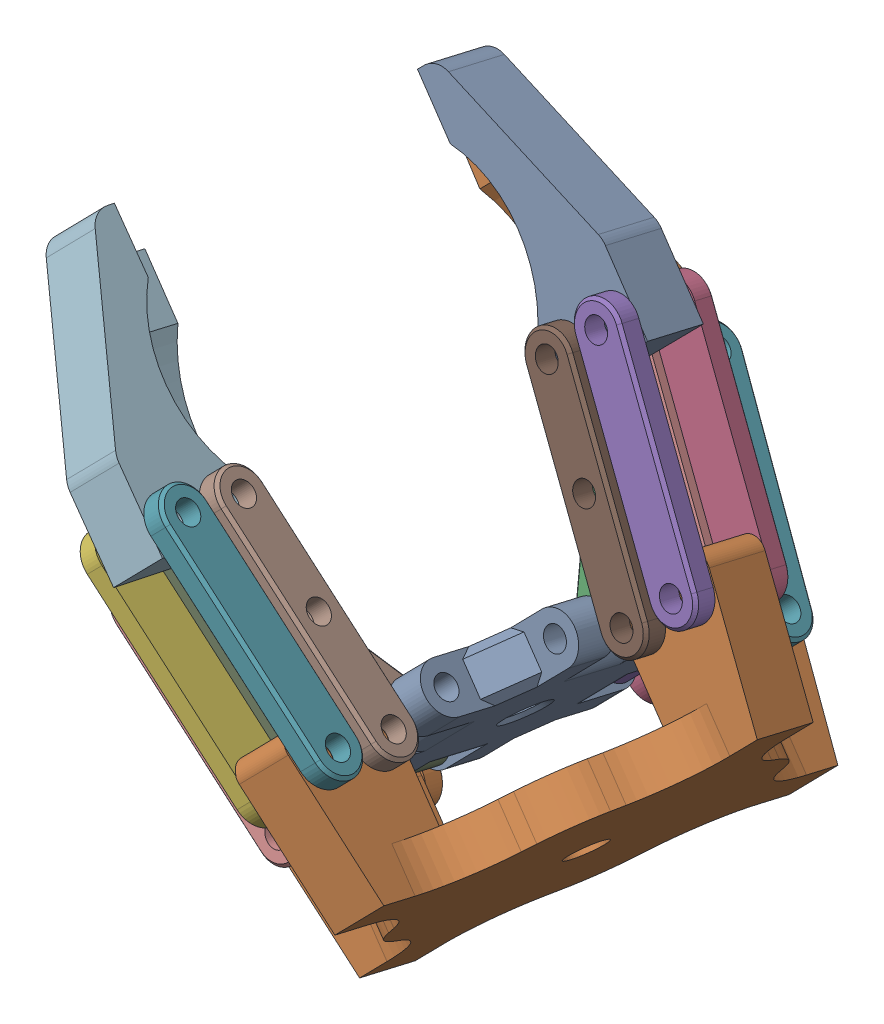
SolidWorks assembly total, configuration Default. Lengths in mm.
Overall size (103.68 109.85 90.72).
26 component instances, 6 part files, 67 mates.
Components (placement in the parent):
- Elevetor_part-1: Elevetor_part [Default] at (64.4019 9.7724 30.449) x (0.689493 0.705559 -0.163663) z (0 0.225963 0.974136) size (39.95 6.2 39.95)
- Gripper1_part-7: Gripper1_part [Default] at (45.2763 21.6653 1.1461) x (-0.017226 0.241873 0.970155) z (0.724087 -0.666096 0.178924) size (13.75 7.7 33.83)
- Connecting_rod_2_part-12: Connecting_rod_2_part [Default] at (53.0008 5.7158 -3.298) x (-0.708443 0.60995 -0.355063) z (-0.150692 0.36076 0.920404) size (33 2.7 6.5)
- Connecting_rod_3_part-10: Connecting_rod_3_part [Default] at (52.9016 7.626 4.2136) x (-0.70843 0.609919 -0.355141) z (-0.150752 0.360811 0.920374) size (33 2.7 6.5)
- Connecting_rod_1_part-5: Connecting_rod_1_part [Default] at (59.8022 9.0845 7.7997) x (0.555901 -0.370654 0.744036) z (-0.464299 0.603988 0.647784) size (19.5 7.7 5.2)
- Connecting_rod_3_part-11: Connecting_rod_3_part [Default] at (60.0724 14.9638 2.5115) x (0.70843 -0.609919 0.355141) z (-0.150752 0.360811 0.920374) size (33 2.7 6.5)
- Connecting_rod_2_part-13: Connecting_rod_2_part [Default] at (60.1715 13.0536 -5.0001) x (0.708443 -0.60995 0.355063) z (-0.150692 0.36076 0.920404) size (33 2.7 6.5)
- Connecting_rod_1_part-6: Connecting_rod_1_part [Default] at (61.1212 17.5589 49.8903) x (-0.555901 0.660356 0.504881) z (-0.464299 0.257131 -0.847531) size (19.5 7.7 5.2)
- Connecting_rod_1_part-7: Connecting_rod_1_part [Default] at (44.4481 -1.6146 33.039) x (0.997863 -0.063651 0.014765) z (0.065341 0.972054 -0.22548) size (19.5 7.7 5.2)
- Connecting_rod_2_part-14: Connecting_rod_2_part [Default] at (33.1537 -5.5281 39.2849) x (-0.851154 0.51134 -0.118612) z (0.524916 0.829139 -0.192329) size (33 2.7 6.5)
- Connecting_rod_3_part-12: Connecting_rod_3_part [Default] at (38.4973 -0.06 38.0165) x (-0.851154 0.51134 -0.118612) z (0.524916 0.829139 -0.192329) size (33 2.7 6.5)
- Gripper1_part-8: Gripper1_part [Default] at (27.5496 9.2689 30.5144) x (0.689493 0.705559 -0.163663) z (0.724292 -0.67166 0.1558) size (13.75 7.7 33.83)
- Connecting_rod_2_part-15: Connecting_rod_2_part [Default] at (33.1537 -7.8781 29.1538) x (-0.851154 0.51134 -0.118612) z (-0.524916 -0.829139 0.192329) size (33 2.7 6.5)
- Connecting_rod_3_part-13: Connecting_rod_3_part [Default] at (38.4973 -2.41 27.8855) x (-0.851154 0.51134 -0.118612) z (-0.524916 -0.829139 0.192329) size (33 2.7 6.5)
- Connecting_rod_1_part-8: Connecting_rod_1_part [Default] at (75.3578 27.439 26.2997) x (-0.113909 0.967795 -0.224492) z (-0.993491 -0.110963 0.025739) size (19.5 7.7 5.2)
- Connecting_rod_2_part-16: Connecting_rod_2_part [Default] at (79.774 39.7793 18.0991) x (-0.564923 0.803802 -0.186452) z (-0.825143 -0.550312 0.127652) size (33 2.7 6.5)
- Connecting_rod_2_part-17: Connecting_rod_2_part [Default] at (79.774 42.1293 28.2301) x (-0.564923 0.803802 -0.186452) z (0.825143 0.550312 -0.127652) size (33 2.7 6.5)
- Connecting_rod_2_part-18: Connecting_rod_2_part [Default] at (52.987 21.0669 62.5177) x (0.708435 -0.703979 -0.050332) z (-0.150727 -0.081241 -0.985231) size (33 2.7 6.5)
- Connecting_rod_2_part-19: Connecting_rod_2_part [Default] at (60.1578 28.4047 60.8156) x (0.708435 -0.703979 -0.050332) z (0.150727 0.081241 0.985231) size (33 2.7 6.5)
- Connecting_rod_3_part-14: Connecting_rod_3_part [Default] at (60.0724 26.7328 53.2481) x (0.70843 -0.703982 -0.050366) z (0.150752 0.081217 0.98523) size (33 2.7 6.5)
- Connecting_rod_3_part-15: Connecting_rod_3_part [Default] at (52.9016 19.395 54.9502) x (-0.70843 0.703982 0.050366) z (0.150752 0.081217 0.98523) size (33 2.7 6.5)
- Connecting_rod_3_part-16: Connecting_rod_3_part [Default] at (74.4082 34.3319 19.3627) x (0.564921 -0.803803 0.186452) z (0.825145 0.55031 -0.127651) size (33 2.7 6.5)
- Connecting_rod_3_part-17: Connecting_rod_3_part [Default] at (74.4082 36.6819 29.4937) x (-0.564921 0.803803 -0.186452) z (0.825145 0.55031 -0.127651) size (33 2.7 6.5)
- Gripper1_part-9: Gripper1_part [Default] at (45.3292 33.3645 51.499) x (-0.011012 -0.215725 -0.976392) z (0.724209 -0.675018 0.140971) size (13.75 7.7 33.83)
- Gripper1_part-10: Gripper1_part [Default] at (63.1142 45.6673 22.0714) x (-0.69236 -0.70289 0.163044) z (0.721553 -0.674452 0.156448) size (13.75 7.7 33.83)
- Base_part-1: Base_part [Default] at (77.0657 -1.9712 33.1731) x (0.689493 0.705559 -0.163663) z (0 0.225963 0.974136) size (69.65 19.1 69.65)
Mates (geometry in assembly coordinates):
- Coincidente1: coincident anti-aligned: plane of Part1-1 through (64.8456 17.6341 42.3811) normal (-0.689493 -0.705559 0.163663); plane of Part2-1 through (67.0909 16.3372 46.2492) normal (0.689493 0.705559 -0.163663)
- Concentrico2: concentric aligned: cylinder of Part1-1 through (78.4331 27.9437 43.557) axis (-0.689493 -0.705559 0.163663) radius 1.5; cylinder of Part2-1 through (67.0909 16.3372 46.2492) axis (-0.689493 -0.705559 0.163663) radius 1.5
- Coincidente3: coincident anti-aligned: plane of Part1-1 through (48.1254 -3.3848 29.4974) normal (0 0.225963 0.974136); plane of Part2-3 through (38.4973 -2.105 29.2005) normal (0 -0.225963 -0.974136)
- Concentrico4: concentric anti-aligned: cylinder of Part1-1 through (52.7667 2.3797 52.6692) axis (0 -0.225963 -0.974136) radius 1.5; cylinder of Part2-3 through (52.7667 -3.0152 29.4117) axis (0 0.225963 0.974136) radius 1.5
- Coincidente4: coincident anti-aligned: plane of Part1-1 through (71.3958 20.4278 23.9738) normal (0 0.225963 0.974136); plane of Part2-4 through (76.0371 20.7975 23.888) normal (0 -0.225963 -0.974136)
- Concentrico5: concentric aligned: cylinder of Part1-1 through (76.0371 17.0804 7.8635) axis (0 0.225963 0.974136) radius 1.5; cylinder of Part2-4 through (76.0371 20.7975 23.888) axis (0 0.225963 0.974136) radius 1.5
- Coincidente28: coincident anti-aligned: plane of Part2-4 through (76.0371 22.5374 31.3889) normal (0 0.225963 0.974136); plane of Part4-9 through (81.8934 25.7265 30.6491) normal (0 -0.225963 -0.974136)
- Concentrico26: concentric anti-aligned: cylinder of Part2-4 through (74.4082 34.6369 20.6778) axis (0 0.225963 0.974136) radius 1.5; cylinder of Part4-9 through (74.4082 36.9869 30.8088) axis (0 -0.225963 -0.974136) radius 1.5
- Coincidente31: coincident anti-aligned: plane of Part4-9 through (81.8934 25.7265 30.6491) normal (0 -0.225963 -0.974136); plane of Part5-6 through (63.1142 46.5373 25.8218) normal (0 0.225963 0.974136)
- Concentrico28: concentric anti-aligned: cylinder of Part4-9 through (66.923 47.6373 28.3383) axis (0 -0.225963 -0.974136) radius 1.5; cylinder of Part5-6 through (66.923 45.2873 18.2073) axis (0 0.225963 0.974136) radius 1.5
- Coincidente32: coincident anti-aligned: plane of Part3-3 through (87.2592 31.1739 29.3855) normal (0 -0.225963 -0.974136); plane of Part5-6 through (63.1142 46.5373 25.8218) normal (0 0.225963 0.974136)
- Concentrico30: concentric anti-aligned: cylinder of Part3-3 through (72.2888 53.0847 27.0747) axis (0 -0.225963 -0.974136) radius 1.5; cylinder of Part5-6 through (72.2888 50.7347 16.9437) axis (0 0.225963 0.974136) radius 1.5
- Coincidente35: coincident anti-aligned: plane of Part2-1 through (67.0909 16.3372 46.2492) normal (0.689493 0.705559 -0.163663); plane of Part4-1 through (49.7548 35.108 54.1364) normal (-0.689493 -0.705559 0.163663)
- Concentrico32: concentric aligned: cylinder of Part2-1 through (59.1415 25.7803 53.469) axis (-0.689493 -0.705559 0.163663) radius 1.5; cylinder of Part4-1 through (61.0032 27.6853 53.0271) axis (-0.689493 -0.705559 0.163663) radius 1.5
- Coincidente36: coincident anti-aligned: plane of Part2-1 through (61.7818 10.9044 47.5094) normal (-0.689493 -0.705559 0.163663); plane of Part4-2 through (63.2191 11.0197 54.0619) normal (0.689493 0.705559 -0.163663)
- Concentrico33: concentric anti-aligned: cylinder of Part2-1 through (59.1415 25.7803 53.469) axis (-0.689493 -0.705559 0.163663) radius 1.5; cylinder of Part4-2 through (51.9708 18.4425 55.1711) axis (0.689493 0.705559 -0.163663) radius 1.5
- Coincidente37: coincident aligned: plane of Part4-1 through (51.1265 36.7491 50.4925) normal (-0.150752 -0.081217 -0.98523); plane of Part4-2 through (60.8676 8.8508 51.3018) normal (-0.150752 -0.081217 -0.98523)
- Coincidente44: coincident anti-aligned: plane of Part4-2 through (63.2191 11.0197 54.0619) normal (0.689493 0.705559 -0.163663); plane of Part5-1 through (42.6746 30.6481 52.1291) normal (-0.689493 -0.705559 0.163663)
- Concentrico37: concentric anti-aligned: cylinder of Part4-2 through (42.5841 27.7702 55.8385) axis (0.689493 0.705559 -0.163663) radius 1.5; cylinder of Part5-1 through (49.7548 35.108 54.1364) axis (-0.689493 -0.705559 0.163663) radius 1.5
- Coincidente45: coincident anti-aligned: plane of Part5-1 through (47.9837 36.0809 50.8689) normal (0.689493 0.705559 -0.163663); plane of Part3-6 through (49.8402 36.7799 61.7034) normal (-0.689493 -0.705559 0.163663)
- Concentrico38: concentric aligned: cylinder of Part5-1 through (49.8402 36.7799 61.7034) axis (-0.689493 -0.705559 0.163663) radius 1.5; cylinder of Part3-6 through (51.7018 38.6849 61.2615) axis (-0.689493 -0.705559 0.163663) radius 1.5
- Coincidente46: coincident anti-aligned: plane of Part5-1 through (42.6746 30.6481 52.1291) normal (-0.689493 -0.705559 0.163663); plane of Part3-5 through (44.5311 31.3471 62.9636) normal (0.689493 0.705559 -0.163663)
- Concentrico39: concentric anti-aligned: cylinder of Part5-1 through (49.8402 36.7799 61.7034) axis (-0.689493 -0.705559 0.163663) radius 1.5; cylinder of Part3-5 through (42.6695 29.4421 63.4055) axis (0.689493 0.705559 -0.163663) radius 1.5
- Coincidente47: coincident anti-aligned: plane of Part2-3 through (38.4973 -0.365 36.7014) normal (0 0.225963 0.974136); plane of Part4-7 through (49.775 -7.1403 38.273) normal (0 -0.225963 -0.974136)
- Concentrico40: concentric anti-aligned: cylinder of Part2-3 through (38.4973 -2.105 29.2005) axis (0 0.225963 0.974136) radius 1.5; cylinder of Part4-7 through (38.4973 0.2451 39.3315) axis (0 -0.225963 -0.974136) radius 1.5
- Coincidente48: coincident anti-aligned: plane of Part2-3 through (38.4973 -2.105 29.2005) normal (0 -0.225963 -0.974136); plane of Part4-8 through (49.775 -8.8802 30.7721) normal (0 0.225963 0.974136)
- Concentrico41: concentric aligned: cylinder of Part2-3 through (38.4973 -2.105 29.2005) axis (0 0.225963 0.974136) radius 1.5; cylinder of Part4-8 through (38.4973 -2.7151 26.5704) axis (0 0.225963 0.974136) radius 1.5
- Coincidente49: coincident aligned: plane of Part4-7 through (48.0691 -9.2249 41.5282) normal (-0.524916 -0.829139 0.192329); plane of Part4-8 through (48.0691 -12.185 28.767) normal (-0.524916 -0.829139 0.192329)
- Coincidente50: coincident anti-aligned: plane of Part4-8 through (49.775 -8.8802 30.7721) normal (0 0.225963 0.974136); plane of Part5-2 through (27.5496 8.399 26.764) normal (0 -0.225963 -0.974136)
- Concentrico42: concentric anti-aligned: cylinder of Part4-8 through (27.2195 4.0602 24.9988) axis (0 0.225963 0.974136) radius 1.5; cylinder of Part5-2 through (27.2195 6.4102 35.1298) axis (0 -0.225963 -0.974136) radius 1.5
- Coincidente51: coincident anti-aligned: plane of Part5-2 through (27.5496 10.1389 34.2649) normal (0 0.225963 0.974136); plane of Part3-8 through (44.4315 -12.6084 39.5414) normal (0 -0.225963 -0.974136)
- Concentrico43: concentric aligned: cylinder of Part5-2 through (21.8759 0.9421 36.3982) axis (0 -0.225963 -0.974136) radius 1.5; cylinder of Part3-8 through (21.8759 1.5522 39.0283) axis (0 -0.225963 -0.974136) radius 1.5
- Coincidente59: coincident anti-aligned: plane of Part3-9 through (44.4315 -14.3483 32.0405) normal (0 0.225963 0.974136); plane of Part5-2 through (27.5496 8.399 26.764) normal (0 -0.225963 -0.974136)
- Concentrico52: concentric anti-aligned: cylinder of Part3-9 through (21.8759 -1.4079 26.2672) axis (0 0.225963 0.974136) radius 1.5; cylinder of Part5-2 through (21.8759 0.9421 36.3982) axis (0 -0.225963 -0.974136) radius 1.5
- Concentrico54: concentric anti-aligned: cylinder of Part1-1 through (62.1566 11.8545 29.966) axis (0.724292 -0.67166 0.1558) radius 2.5; cylinder of new_part-1 through (77.0657 -1.9712 33.1731) axis (-0.724292 0.67166 -0.1558) radius 2.5
- Concentrico55: concentric aligned: circle of Part4-8; cylinder of new_part-1 through (49.775 -8.8689 30.8208) axis (0 -0.225963 -0.974136) radius 1.5
- Concentrico56: concentric anti-aligned: cylinder of Part4-2 through (61.3575 9.1147 54.5038) axis (0.689493 0.705559 -0.163663) radius 1.5; cylinder of new_part-1 through (63.1847 10.9845 54.0701) axis (-0.689493 -0.705559 0.163663) radius 1.5
- Concentrico57: concentric aligned: circle of Part3-5; cylinder of new_part-1 through (63.2701 12.6564 61.638) axis (-0.689493 -0.705559 0.163663) radius 1.5
- Tangente1: tangent: cylinder of Part3-6 through (70.4754 20.0295 59.9277) axis (-0.689493 -0.705559 0.163663) radius 1.5; circle of new_part-1
- Concentrico58: concentric aligned: cylinder of Part3-6 through (70.4754 20.0295 59.9277) axis (-0.689493 -0.705559 0.163663) radius 1.5; cylinder of new_part-1 through (63.2701 12.6564 61.638) axis (-0.689493 -0.705559 0.163663) radius 1.5
- Concentrico61: concentric anti-aligned: cylinder of Part3-9 through (44.4315 -14.9584 29.4104) axis (0 0.225963 0.974136) radius 1.5; cylinder of new_part-1 through (44.4315 -14.337 32.0892) axis (0 -0.225963 -0.974136) radius 1.5
- Concentrico62: concentric aligned: cylinder of Part3-8 through (44.4315 -11.9983 42.1715) axis (0 -0.225963 -0.974136) radius 1.5; cylinder of new_part-1 through (44.4315 -14.337 32.0892) axis (0 -0.225963 -0.974136) radius 1.5
- Coincidente64: coincident anti-aligned: plane of Part3-2 through (87.2592 29.434 21.8847) normal (0 0.225963 0.974136); plane of Part5-6 through (63.1142 44.7973 18.321) normal (0 -0.225963 -0.974136)
- Concentrico67: concentric aligned: cylinder of Part3-2 through (72.2888 50.1246 14.3136) axis (0 0.225963 0.974136) radius 1.5; cylinder of Part5-6 through (72.2888 50.7347 16.9437) axis (0 0.225963 0.974136) radius 1.5
- Concentrico68: concentric anti-aligned: cylinder of Part3-2 through (87.2592 28.8239 19.2545) axis (0 0.225963 0.974136) radius 1.5; circle of new_part-1
- Coincidente65: coincident anti-aligned: plane of Part4-4 through (66.923 45.2873 18.2073) normal (0 0.225963 0.974136); plane of Part5-6 through (63.1142 44.7973 18.321) normal (0 -0.225963 -0.974136)
- Concentrico69: concentric aligned: cylinder of Part4-4 through (66.923 44.6772 15.5771) axis (0 0.225963 0.974136) radius 1.5; cylinder of Part5-6 through (66.923 45.2873 18.2073) axis (0 0.225963 0.974136) radius 1.5
- Concentrico70: concentric anti-aligned: circle of Part4-4; cylinder of new_part-1 through (81.8934 25.7378 30.6978) axis (0 0.225963 0.974136) radius 1.5
- Concentrico71: concentric anti-aligned: cylinder of Part4-9 through (81.8934 26.3366 33.2793) axis (0 -0.225963 -0.974136) radius 1.5; cylinder of new_part-1 through (81.8934 25.7378 30.6978) axis (0 0.225963 0.974136) radius 1.5
- Concentrico72: concentric aligned: circle of Part3-3; cylinder of new_part-1 through (87.2592 31.1852 29.4342) axis (0 0.225963 0.974136) radius 1.5
- Concentrico47: concentric aligned: cylinder of Part4-10 through (42.5841 14.7549 -0.2711) axis (0.689493 0.705559 -0.163663) radius 1.5; cylinder of Part5-7 through (44.4113 16.6247 -0.7048) axis (0.689493 0.705559 -0.163663) radius 1.5
- Concentrico48: concentric anti-aligned: cylinder of Part4-11 through (51.6165 23.9977 -2.4151) axis (-0.689493 -0.705559 0.163663) radius 1.5; cylinder of Part5-7 through (44.4113 16.6247 -0.7048) axis (0.689493 0.705559 -0.163663) radius 1.5
- Coincidente56: coincident anti-aligned: plane of Part5-7 through (42.6218 18.9489 1.7762) normal (-0.689493 -0.705559 0.163663); plane of Part3-12 through (63.3185 -1.4135 1.1857) normal (0.689493 0.705559 -0.163663)
- Concentrico49: concentric aligned: cylinder of Part5-7 through (44.5448 14.7501 -8.2235) axis (0.689493 0.705559 -0.163663) radius 1.5; cylinder of Part3-12 through (42.6831 12.8451 -7.7816) axis (0.689493 0.705559 -0.163663) radius 1.5
- Coincidente57: coincident anti-aligned: plane of Part5-7 through (47.9309 24.3817 0.516) normal (0.689493 0.705559 -0.163663); plane of Part3-13 through (49.8539 20.1829 -9.4837) normal (-0.689493 -0.705559 0.163663)
- Concentrico50: concentric anti-aligned: cylinder of Part5-7 through (44.5448 14.7501 -8.2235) axis (0.689493 0.705559 -0.163663) radius 1.5; cylinder of Part3-13 through (51.7155 22.088 -9.9256) axis (-0.689493 -0.705559 0.163663) radius 1.5
- Coincidente58: coincident aligned: plane of Part3-12 through (61.9466 -4.491 -1.3637) normal (0.150692 -0.36076 -0.920404); plane of Part3-13 through (52.2052 20.9155 -12.9169) normal (0.150692 -0.36076 -0.920404)
- Coincidente54: coincident anti-aligned: plane of Part2-5 through (53.8324 8.5785 3.9926) normal (-0.689493 -0.705559 0.163663); plane of Part4-10 through (63.2191 0.4971 8.6983) normal (0.689493 0.705559 -0.163663)
- Concentrico46: concentric anti-aligned: cylinder of Part2-5 through (59.1415 14.0113 2.7324) axis (-0.689493 -0.705559 0.163663) radius 1.5; cylinder of Part4-10 through (51.9708 6.6735 4.4345) axis (0.689493 0.705559 -0.163663) radius 1.5
- Coincidente55: coincident aligned: plane of Part4-11 through (52.1064 22.8251 -5.4063) normal (0.150752 -0.360811 -0.920374); plane of Part4-10 through (61.8475 -2.5806 6.1489) normal (0.150752 -0.360811 -0.920374)
- Coincidente53: coincident anti-aligned: plane of Part2-5 through (59.1415 14.0113 2.7324) normal (0.689493 0.705559 -0.163663); plane of Part4-11 through (49.7548 22.0927 -1.9732) normal (-0.689493 -0.705559 0.163663)
- Concentrico45: concentric aligned: cylinder of Part2-5 through (59.1415 14.0113 2.7324) axis (-0.689493 -0.705559 0.163663) radius 1.5; cylinder of Part4-11 through (61.0032 15.9163 2.2905) axis (-0.689493 -0.705559 0.163663) radius 1.5
- Concentrico79: concentric aligned: cylinder of Part3-12 through (61.4569 -3.3185 1.6276) axis (0.689493 0.705559 -0.163663) radius 1.5; cylinder of new_part-1 through (68.6276 4.0193 -0.0745) axis (0.689493 0.705559 -0.163663) radius 1.5
- Concentrico80: concentric aligned: cylinder of Part4-10 through (61.3575 -1.4079 9.1402) axis (0.689493 0.705559 -0.163663) radius 1.5; cylinder of new_part-1 through (68.4938 5.8946 7.4462) axis (0.689493 0.705559 -0.163663) radius 1.5
- Coincidente71: coincident anti-aligned: plane of Part1-1 through (64.8456 10.0079 9.5041) normal (-0.689493 -0.705559 0.163663); plane of Part2-5 through (59.1415 14.0113 2.7324) normal (0.689493 0.705559 -0.163663)
- Concentrico81: concentric anti-aligned: cylinder of Part1-1 through (50.3707 -8.3989 17.341) axis (0.689493 0.705559 -0.163663) radius 1.5; cylinder of Part2-5 through (67.0909 8.711 13.3722) axis (-0.689493 -0.705559 0.163663) radius 1.5
- Coincidente72: coincident anti-aligned: plane of Part3-13 through (49.8539 20.1829 -9.4837) normal (-0.689493 -0.705559 0.163663); plane of new_part-1 through (75.7367 -3.5368 -2.6995) normal (0.689493 0.705559 -0.163663)
